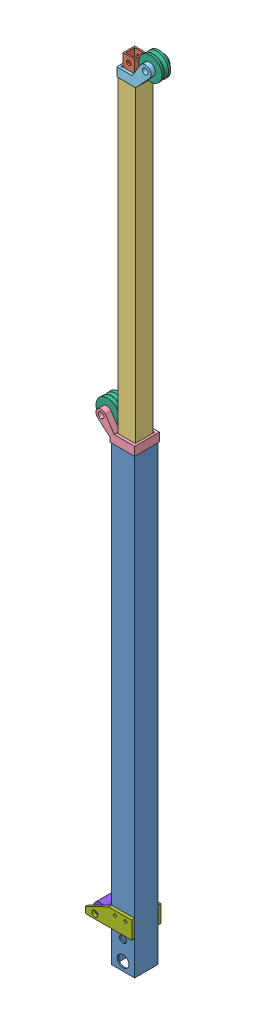
SolidWorks assembly Climber, configuration Default. Lengths in mm.
Overall size (72.97 874.48 31.75).
10 component instances, 8 part files, 28 mates.
Components (placement in the parent):
- Tubes-1: Tubes [Default] at origin size (25.4 501.65 25.4)
- Tubes3-1: Tubes3 [Default] at (0 355.3684 0) size (12.7 508 12.7)
- Tubes2-1: Tubes2 [Default] at (1.0954 352.8284 0) size (19.05 495.3 19.05)
- Cap-1: Cap [Default] at (0 504.19 0) x (-1 0 0) z (0 0 1) size (42.42 26.35 26.99)
- Cap2-1: Cap2 [Default] at (1.0954 850.6684 0) x (-1 0 0) z (0 0 1) size (37.5 26.99 20.64)
- Roller-1: Roller [Default] at (21.9234 861.7809 -4.7942) size (25.4 25.4 9.59)
- Roller-2: Roller [2nd Stage] at (-23.2093 515.3025 -6.3182) size (25.4 25.4 12.64)
- Mount-1: Mount [Default] at (0.02 46.8188 12.7) size (50.8 19.05 3.17)
- Mount-2: Mount [Default] at (0.02 46.8188 -15.875) size (50.8 19.05 3.17)
- Space-1: Space [Default] at (-27.5695 42.3738 -10.16) x (0.713951 -0.700196 0) z (0 0 1) size (15.24 15.24 20.32)
Mates (geometry in assembly coordinates):
- Coincident11: coincident anti-aligned: plane of Tubes2-1 through (1.0954 848.1284 0) normal (0 1 0); plane of Cap2-1 through (1.0954 848.1284 0) normal (0 -1 0)
- Width13: width anti-aligned: plane of Tubes2-1 through (-8.4296 848.1284 -9.525) normal (0 0 -1); plane of Tubes2-1 through (-8.4296 848.1284 9.525) normal (0 0 1); plane of Tubes-1 through (-11.1125 501.65 -11.1125) normal (0 0 1); plane of Tubes-1 through (-11.1125 501.65 11.1125) normal (0 0 -1)
- Coincident14: coincident aligned: plane of Tubes2-1 through (1.0954 352.8284 0) normal (0 0 1)
- Coincident15: coincident aligned: plane of Tubes-1 through (0 0 0) normal (0 0 1)
- Coincident16: coincident aligned: plane of Tubes-1 through (0 0 0) normal (1 0 0)
- Coincident17: coincident aligned: plane of Tubes-1 through (0 0 0) normal (0 1 0)
- Coincident18: coincident aligned: plane of Tubes3-1 through (0 355.3684 0) normal (0 0 1)
- Coincident19: coincident aligned: plane of Tubes3-1 through (0 355.3684 0) normal (1 0 0)
- Coincident20: coincident aligned: plane of Tubes2-1 through (1.0954 352.8284 0) normal (0 0 1); plane of Cap2-1 through (1.0954 850.6684 0) normal (0 0 1)
- Coincident21: coincident anti-aligned: plane of Tubes2-1 through (1.0954 352.8284 0) normal (1 0 0); plane of Cap2-1 through (1.0954 850.6684 0) normal (-1 0 0)
- LimitDistance1: limit distance = 12.7 mm aligned: plane of Tubes3-1 through (0 863.3684 0) normal (0 1 0); plane of Cap2-1 through (1.0954 850.6684 0) normal (0 1 0)
- Coincident22: coincident aligned: plane of Cap-1 through (0 504.19 0) normal (0 0 1)
- Coincident23: coincident anti-aligned: plane of Tubes-1 through (0 501.65 0) normal (0 1 0); plane of Cap-1 through (0 501.65 0) normal (0 -1 0)
- Coincident24: coincident anti-aligned: plane of Cap-1 through (0 504.19 0) normal (-1 0 0)
- Width18: width aligned: plane of Cap-1 through (-8.9218 501.65 0) normal (1 0 0); plane of Cap-1 through (11.1125 501.65 0) normal (-1 0 0); plane of Tubes2-1 through (10.6204 848.1284 -9.525) normal (1 0 0); plane of Tubes2-1 through (-8.4296 848.1284 -9.525) normal (-1 0 0)
- LimitDistance2: limit distance = 346.4784 mm aligned: plane of Cap2-1 through (1.0954 850.6684 0) normal (0 1 0); plane of Cap-1 through (0 504.19 0) normal (0 1 0)
- Concentric1: concentric anti-aligned: cylinder of Cap2-1 through (21.9234 861.7809 5.5563) axis (0 0 1) radius 3.175; cylinder of Roller-1 through (21.9234 861.7809 4.7942) axis (0 0 -1) radius 3.175
- Width19: width anti-aligned: plane of Roller-1 through (21.9234 861.7809 4.7942) normal (0 0 1); plane of Roller-1 through (21.9234 861.7809 -4.7942) normal (0 0 -1); plane of Cap2-1 through (1.0954 850.6684 5.5563) normal (0 0 -1); plane of Cap2-1 through (21.9234 861.7809 -5.5563) normal (0 0 1)
- Concentric2: concentric aligned: cylinder of Cap-1 through (-23.2093 515.3025 -7.1437) axis (0 0 -1) radius 3.175; cylinder of Roller-2 through (-23.2093 515.3025 6.3182) axis (0 0 -1) radius 3.175
- Width20: width anti-aligned: plane of Roller-2 through (-23.2093 515.3025 -6.3182) normal (0 0 -1); plane of Roller-2 through (-23.2093 515.3025 6.3182) normal (0 0 1); plane of Cap-1 through (-23.2093 515.3025 -7.1437) normal (0 0 1); plane of Cap-1 through (0 504.19 7.1437) normal (0 0 -1)
- Coincident32: coincident anti-aligned: plane of Tubes-1 through (-12.7 501.65 12.7) normal (0 0 1); plane of Mount-1 through (0.02 46.8188 12.7) normal (0 0 -1)
- Concentric5: concentric aligned: cylinder of Mount-1 through (-27.5695 42.3738 15.875) axis (0 0 -1) radius 3.175; cylinder of Space-1 through (-27.5695 42.3738 10.16) axis (0 0 -1) radius 3.175
- Width24: width anti-aligned: plane of Mount-2 through (0.02 46.8188 -12.7) normal (0 0 1); plane of Mount-1 through (0.02 46.8188 12.7) normal (0 0 -1); plane of Space-1 through (-27.5695 42.3738 -10.16) normal (0 0 -1); plane of Space-1 through (-27.5695 42.3738 10.16) normal (0 0 1)
- Concentric7: concentric aligned: cylinder of Mount-2 through (-27.5695 42.3738 -12.7) axis (0 0 -1) radius 3.175; cylinder of Space-1 through (-27.5695 42.3738 10.16) axis (0 0 -1) radius 3.175
- Parallel1: parallel aligned: plane of Mount-1 through (0.02 56.3438 15.875) normal (0 1 0); plane of Mount-2 through (0.02 56.3438 -12.7) normal (0 1 0)
- Width25: width anti-aligned: plane of Mount-2 through (0.02 46.8188 -15.875) normal (0 0 -1); plane of Mount-1 through (0.02 46.8188 15.875) normal (0 0 1); plane of Tubes-1 through (-12.7 501.65 12.7) normal (0 0 1); plane of Tubes-1 through (-12.7 501.65 -12.7) normal (0 0 -1)
- Concentric16: concentric aligned: cylinder of Tubes-1 through (5.7096 51.5178 12.7) axis (0 0 -1) radius 1.5875; cylinder of Mount-2 through (5.7096 51.5178 -12.7) axis (0 0 -1) radius 1.5875
- Parallel5: parallel aligned: plane of Tubes-1 through (12.7 501.65 -12.7) normal (1 0 0); plane of Mount-2 through (12.72 46.8188 -12.7) normal (1 0 0)
